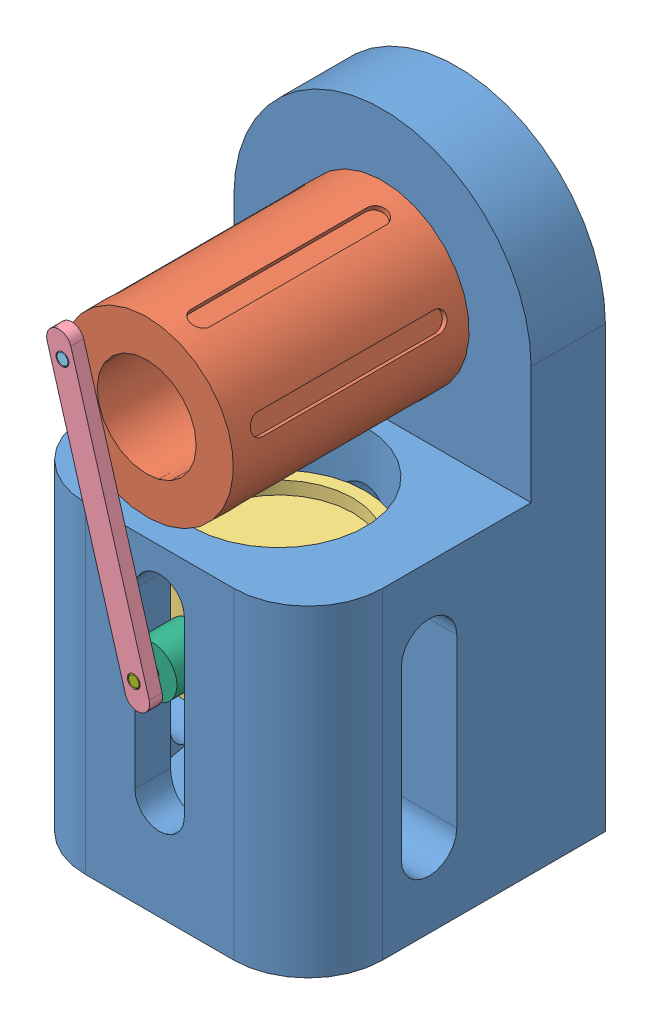
SolidWorks assembly DRFT21-22, configuration Default. Lengths in mm.
Overall size (76.2 150.88 82.8).
7 component instances, 7 part files, 13 mates.
Components (placement in the parent):
- DRFT21-22A-1: DRFT21-22A [Default] at (12.9565 -67.2899 -12.3727) size (76.2 150.88 76.2)
- DRFT21-22B ROTOR-1: DRFT21-22B ROTOR [Default] at (12.9565 45.4861 29.0293) x (0.278169 0.960532 0) z (0 0 1) size (44.45 44.45 79.5)
- DRFT21-22C-1: DRFT21-22C [Default] at (12.9565 -11.6111 -4.7527) x (1 0 0) z (0 1 0) size (44.45 44.45 25.4)
- DRFT21-22D-1: DRFT21-22D [Default] at (13.85 -14.6578 29.0293) x (-0.281406 0.959589 0) z (0 0 1) size (77.72 6.35 3.3)
- DRFT21-22E-1: DRFT21-22E [Default] at (-5.3416 50.7852 32.3313) x (0.836849 0.547434 0) z (0 0 1) size (3.3 3.3 15.88)
- DRFT21-22F-1: DRFT21-22F [Default] at (12.9565 -11.6111 27.6323) x (0.320623 -0.947207 0) z (0 0 1) size (12.7 12.7 10.16)
- DRFT21-22G-1: DRFT21-22G [Default] at (12.9565 -11.6111 32.3313) size (3.17 3.17 22.23)
Mates (geometry in assembly coordinates):
- Concentric1: concentric aligned: cylinder of DRFT21-22A-1 through (12.9565 45.4861 -31.4227) axis (0 0 1) radius 9.525; cylinder of DRFT21-22B ROTOR-1 through (12.9565 45.4861 29.0293) axis (0 0 1) radius 9.525
- Coincident1: coincident anti-aligned: plane of DRFT21-22A-1 through (-25.1435 83.5861 -31.4227) normal (0 0 1); plane of DRFT21-22B ROTOR-1 through (19.1016 66.8447 -31.4227) normal (0 0 -1)
- Concentric2: concentric aligned: cylinder of DRFT21-22B ROTOR-1 through (18.2237 63.7935 29.0293) axis (0 0 1) radius 1.651; cylinder of DRFT21-22E-1 through (18.2237 63.7935 16.4563) axis (0 0 1) radius 1.651
- Coincident2: coincident aligned: plane of DRFT21-22D-1 through (12.6993 -4.1814 32.3313) normal (0 0 1); plane of DRFT21-22E-1 through (18.2237 63.7935 32.3313) normal (0 0 1)
- Concentric3: concentric anti-aligned: cylinder of DRFT21-22D-1 through (18.2237 63.7935 32.3313) axis (0 0 -1) radius 1.651; cylinder of DRFT21-22E-1 through (18.2237 63.7935 16.4563) axis (0 0 1) radius 1.651
- Concentric4: concentric anti-aligned: cylinder of DRFT21-22D-1 through (12.9565 -1.0169 32.3313) axis (0 0 -1) radius 1.651; cylinder of DRFT21-22G-1 through (12.9565 -1.0169 10.1063) axis (0 0 1) radius 1.5875
- Coincident3: coincident aligned: plane of DRFT21-22D-1 through (12.6993 -4.1814 32.3313) normal (0 0 1); plane of DRFT21-22G-1 through (12.9565 -1.0169 32.3313) normal (0 0 1)
- Concentric5: concentric aligned: cylinder of DRFT21-22F-1 through (12.9565 -1.0169 17.4723) axis (0 0 1) radius 6.35; cylinder of DRFT21-22G-1 through (12.9565 -1.0169 10.1063) axis (0 0 1) radius 1.5875
- Concentric6: concentric anti-aligned: cylinder of DRFT21-22A-1 through (12.9565 -54.5899 -4.7527) axis (0 1 0) radius 22.225; cylinder of DRFT21-22C-1 through (12.9565 -1.0169 -4.7527) axis (0 -1 0) radius 22.225
- Concentric8: concentric aligned: cylinder of DRFT21-22C-1 through (12.9565 -1.0169 17.4723) axis (0 0 1) radius 1.5875; cylinder of DRFT21-22G-1 through (12.9565 -1.0169 10.1063) axis (0 0 1) radius 1.5875
- Tangent2: tangent anti-aligned: cylinder of DRFT21-22C-1 through (12.9565 -1.0169 -4.7527) axis (0 -1 0) radius 22.225; plane of DRFT21-22F-1 through (12.9565 -1.0169 17.4723) normal (0 0 -1)
- Coincident5: coincident anti-aligned: plane of DRFT21-22B ROTOR-1 through (16.468 57.691 29.0293) normal (0 0 1); plane of DRFT21-22D-1 through (12.6993 -4.1814 29.0293) normal (0 0 -1)
- Tangent3: tangent anti-aligned: plane of DRFT21-22A-1 through (6.6065 -41.8899 -50.4737) normal (1 0 0); cylinder of DRFT21-22F-1 through (12.9565 -1.0169 17.4723) axis (0 0 1) radius 6.35
